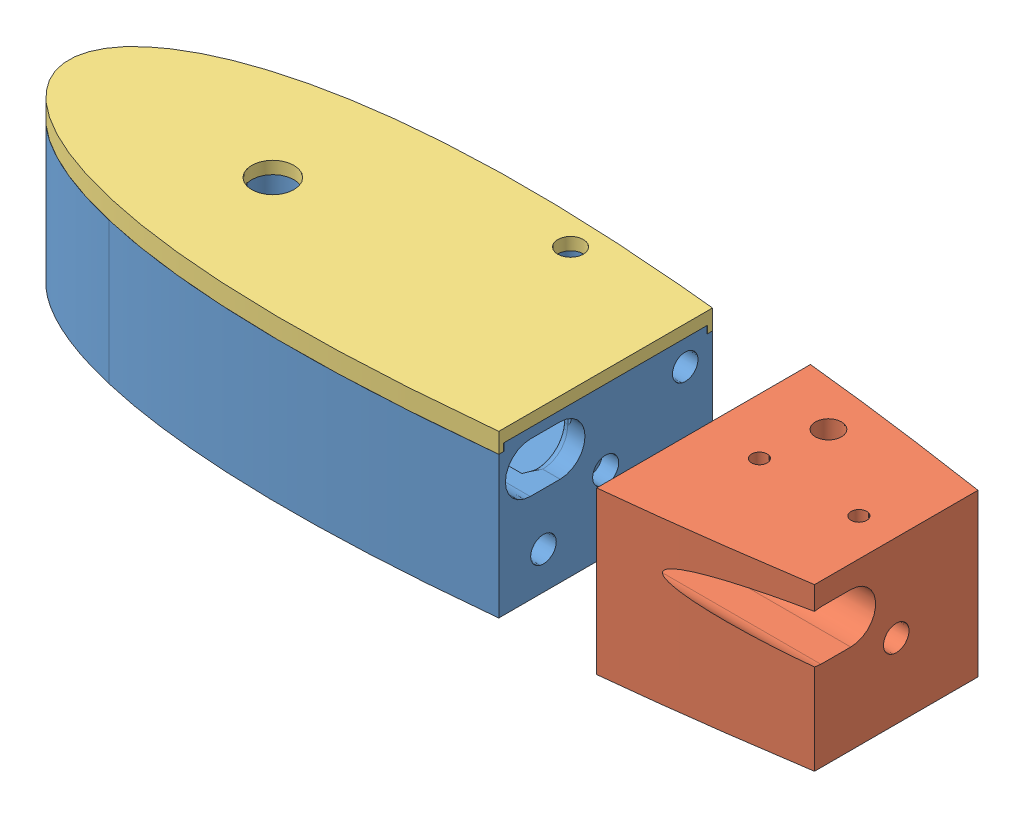
SolidWorks assembly Test assem, configuration Default. Lengths in mm.
Overall size (474.95 82.55 211.81).
3 component instances, 3 part files, 6 mates.
Components (placement in the parent):
- MAST HALF FINAL-1: MAST HALF FINAL [Default] at (-29.4317 247.4926 212.5087) x (1 0 0) z (0 -1 0) size (279.71 147.64 76.2)
- TRIM TAB HALF FINAL-1: TRIM TAB HALF FINAL [Default] at (20.5683 247.4926 212.5087) x (1 0 0) z (0 -1 0) size (102.16 109.14 82.55)
- MAST HALF FINAL Cover-1: MAST HALF FINAL Cover [Default] at (-29.4317 247.4926 212.5087) x (1 0 0) z (0 -1 0) size (371.53 211.81 10.16)
Mates (geometry in assembly coordinates):
- LimitDistance1: limit distance = 50 mm anti-aligned: plane of MAST HALF FINAL-1 through (244.6296 171.2926 283.0755) normal (1 0 0); plane of TRIM TAB HALF FINAL-1 through (294.6296 171.2926 284.6933) normal (-1 0 0)
- Coincident3: coincident aligned: plane of MAST HALF FINAL-1 through (-29.4317 247.4926 212.5087) normal (0 0 1); plane of TRIM TAB HALF FINAL-1 through (20.5683 247.4926 212.5087) normal (0 0 1)
- LimitDistance2: limit distance = 0 mm anti-aligned: plane of MAST HALF FINAL Cover-1 through (-29.4317 247.4926 212.5087) normal (0 -1 0); plane of MAST HALF FINAL-1 through (-29.4317 247.4926 212.5087) normal (0 1 0)
- Coincident5: coincident aligned: plane of MAST HALF FINAL-1 through (244.6296 171.2926 283.0755) normal (1 0 0); plane of MAST HALF FINAL Cover-1 through (244.6296 171.2926 283.0755) normal (1 0 0)
- Concentric1: concentric aligned: cylinder of MAST HALF FINAL-1 through (74.7075 247.4926 212.5087) axis (0 -1 0) radius 10.795; cylinder of MAST HALF FINAL Cover-1 through (74.7075 247.4926 212.5087) axis (0 -1 0) radius 10.795
- Coincident6: coincident aligned: plane of MAST HALF FINAL-1 through (-29.4317 171.2926 212.5087) normal (0 -1 0); plane of TRIM TAB HALF FINAL-1 through (20.5683 171.2926 212.5087) normal (0 -1 0)
